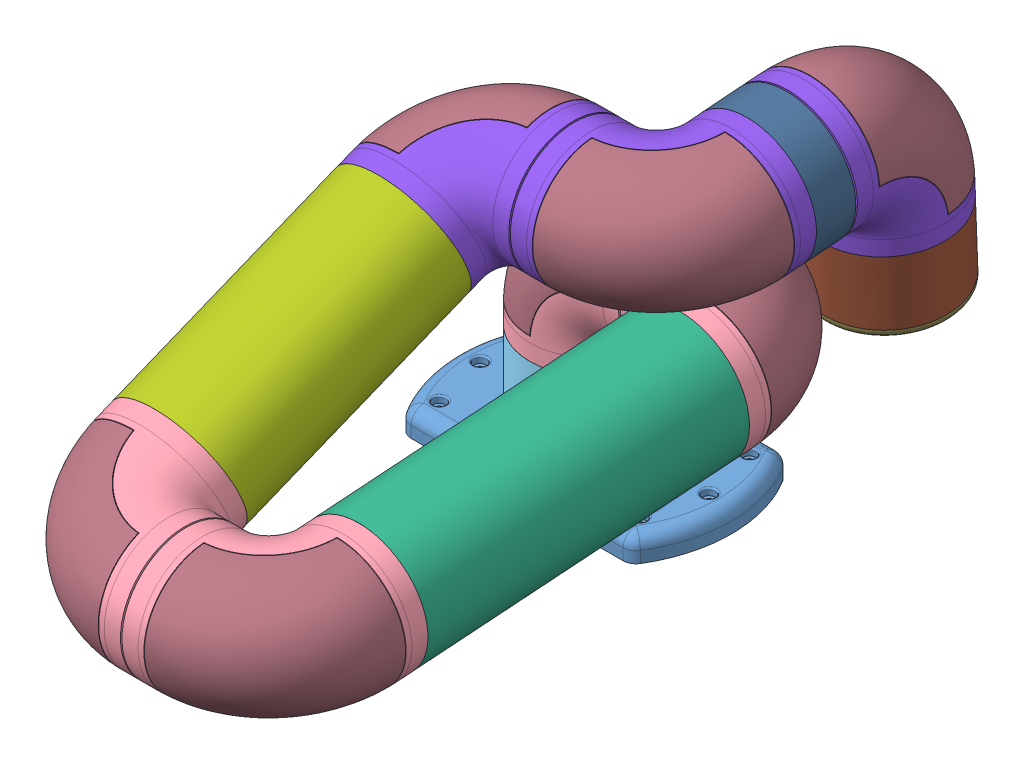
SolidWorks assembly LEG_ACTIVE, configuration 默认. Lengths in mm.
Overall size (249.75 258.63 494.76).
28 component instances, 13 part files, 66 mates.
Components (placement in the parent):
- A1-1: A1 [默认] at (-3.0825 -30.4263 170) size (170 15 96)
- 4340_sim-1: 4340_sim [默认] at (-3.0825 -31.4263 170) size (57 53.25 57)
- A2-1: A2 [默认] at (-3.0825 -0.4263 170) x (0.707107 0 -0.707107) z (-0.707107 0 -0.707107) size (80 15 80)
- B1-1: B1 [默认] at (-3.0825 39.8237 170) size (96.96 109.09 84.56)
- L1-1: L1 [默认] at (-3.0825 0.5237 170) size (80 39.3 80)
- 4340_sim-2: 4340_sim [默认] at (9.7675 94.8237 170) x (0 -1 0) z (0 0 1) size (57 53.25 57)
- B1-2: B1 [默认] at (107.8675 90.9989 224.8669) x (-1 0 0) z (0 -0.997579 -0.06954) size (96.96 109.09 84.56)
- L2-1: L2 [默认] at (107.8675 77.0909 424.3827) x (1 0 0) z (0 0.997579 0.06954) size (80 200 80)
- B1-3: B1 [默认] at (107.8675 77.0909 424.3827) x (-1 0 0) z (0 0.997579 0.06954) size (96.96 109.09 84.56)
- 4340_sim-3: 4340_sim [默认] at (95.0175 73.2662 479.2495) x (0 1 0) z (0 0 1) size (57 53.25 57)
- B1-4: B1 [默认] at (-3.0825 93.8666 428.2533) x (1 0 0) z (0 -0.927205 -0.374554) size (96.96 109.09 84.56)
- L3-1: L3 [默认] at (-3.0825 150.0497 289.1725) x (1 0 0) z (0 -0.927205 -0.374554) size (80 150 80)
- B2-1: B2 [默认] at (-3.0825 150.0497 289.1725) x (1 0 0) z (0 0.927205 0.374554) size (96.96 109.09 84.56)
- B2-2: B2 [默认] at (107.9175 174.8831 183.3393) x (-1 0 0) z (0 0.997034 0.076963) size (96.96 109.09 84.56)
- DM4310_sim-1: DM4310_sim [默认] at (5.6139 -14.4916 258.1062) x (0 -0.117702 -0.993049) z (0.993049 -0.116884 0.013854) size (57 61.9 51.54)
- DM4310_sim-2: DM4310_sim [默认] at (106.1306 358.8556 219.409) x (0.999793 0.020275 0.001565) z (-0.002394 0.193757 -0.981047) size (57 61.9 51.54)
- L4-1: L4 [默认] at (107.9175 174.8831 183.3393) x (1 0 0) z (0 0.997034 0.076963) size (80 24.5 80)
- B2-3: B2 [默认] at (105.6912 126.2867 98.8486) x (0 -0.076963 0.997034) z (-0.99918 0.040357 0.003115) size (96.96 109.09 84.56)
- DM4310_sim-3: DM4310_sim [默认] at (166.0013 159.1883 -75.5941) x (0.950216 -0.062177 0.305326) z (-0.003831 -0.982146 -0.188081) size (57 61.9 51.54)
- L6-1: L6 [默认] at (103.9912 84.4456 95.6188) x (-0.798046 0.078544 -0.597456) z (0.601235 0.037187 -0.798206) size (80 42 80)
- L7-1: L7 [默认] at (103.9912 84.4456 95.6188) x (0.982582 -0.053657 0.177917) z (0.18137 0.068359 -0.981036) size (80 14.5 80)
- C1-1: C1 [默认] at (107.8675 90.9989 224.8669) x (-1 0 0) z (0 -0.997579 -0.06954) size (83.14 83.47 85.73)
- C1-2: C1 [默认] at (-3.0825 39.8237 170) size (83.14 83.47 85.73)
- C1-3: C1 [默认] at (107.8675 77.0909 424.3827) x (-1 0 0) z (0 0.997579 0.06954) size (83.14 83.47 85.73)
- C1-4: C1 [默认] at (-3.0825 93.8666 428.2533) x (1 0 0) z (0 -0.927205 -0.374554) size (83.14 83.47 85.73)
- C1-5: C1 [默认] at (-3.0825 150.0497 289.1725) x (1 0 0) z (0 0.927205 0.374554) size (83.14 83.47 85.73)
- C1-6: C1 [默认] at (107.9175 174.8831 183.3393) x (-1 0 0) z (0 0.997034 0.076963) size (83.14 83.47 85.73)
- C1-7: C1 [默认] at (105.6912 126.2867 98.8486) x (0 -0.076963 0.997034) z (-0.99918 0.040357 0.003115) size (83.14 83.47 85.73)
Mates (geometry in assembly coordinates):
- 重合1: coincident anti-aligned: plane of A1-1 through (-3.0825 -15.4263 170) normal (0 1 0); plane of 4340_sim-1 through (-3.0825 -15.4263 170) normal (0 -1 0)
- 同心1: concentric aligned: cylinder of A1-1 through (-16.5176 -15.4263 183.435) axis (0 -1 0) radius 1.6; cylinder of 4340_sim-1 through (-16.5176 -11.4263 183.435) axis (0 -1 0) radius 1.5
- 同心2: concentric aligned: cylinder of A1-1 through (10.3525 -15.4263 156.565) axis (0 -1 0) radius 1.6; cylinder of 4340_sim-1 through (10.3525 -11.4263 156.565) axis (0 -1 0) radius 1.5
- 重合2: coincident anti-aligned: plane of A1-1 through (-3.0825 -15.4263 170) normal (0 1 0); plane of A2-1 through (-3.0825 -15.4263 170) normal (0 -1 0)
- 同心3: concentric anti-aligned: cylinder of A1-1 through (21.3127 -15.4263 194.3952) axis (0 -1 0) radius 1.6; cylinder of A2-1 through (21.3127 -15.4263 194.3952) axis (0 1 0) radius 1.6
- 同心4: concentric anti-aligned: cylinder of A1-1 through (21.3127 -15.4263 145.6048) axis (0 -1 0) radius 1.6; cylinder of A2-1 through (21.3127 -15.4263 145.6048) axis (0 1 0) radius 1.6
- 重合3: coincident anti-aligned: plane of 4340_sim-1 through (-3.0825 37.8237 170) normal (0 1 0); plane of B1-1 through (-3.0825 37.8237 170) normal (0 -1 0)
- 同心5: concentric anti-aligned: cylinder of 4340_sim-1 through (-3.0825 36.8237 170) axis (0 -1 0) radius 28.5; cylinder of B1-1 through (-3.0825 27.8237 170) axis (0 1 0) radius 33.5
- 同心6: concentric anti-aligned: cylinder of B1-1 through (-3.0825 37.8237 170) axis (0 1 0) radius 37.8; cylinder of L1-1 through (-3.0825 39.8237 170) axis (0 -1 0) radius 38
- 重合4: coincident anti-aligned: plane of B1-1 through (-3.0825 39.8237 170) normal (0 -1 0); plane of L1-1 through (-3.0825 39.8237 170) normal (0 1 0)
- 重合5: coincident anti-aligned: plane of B1-1 through (25.7675 94.8237 170) normal (1 0 0); plane of 4340_sim-2 through (25.7675 94.8237 170) normal (-1 0 0)
- 同心7: concentric anti-aligned: cylinder of B1-1 through (-45.0452 108.2587 183.435) axis (1 0 0) radius 1.6; cylinder of 4340_sim-2 through (29.7675 108.2587 183.435) axis (-1 0 0) radius 1.5
- 同心8: concentric anti-aligned: cylinder of B1-1 through (-45.0452 81.3886 156.565) axis (1 0 0) radius 1.6; cylinder of 4340_sim-2 through (29.7675 81.3886 156.565) axis (-1 0 0) radius 1.5
- 重合6: coincident anti-aligned: plane of 4340_sim-2 through (79.0175 94.8237 170) normal (1 0 0); plane of B1-2 through (79.0175 94.8237 170) normal (-1 0 0)
- 同心9: concentric aligned: cylinder of 4340_sim-2 through (78.0175 94.8237 170) axis (-1 0 0) radius 28.5; cylinder of B1-2 through (62.8675 94.8237 170) axis (-1 0 0) radius 37
- 同心10: concentric anti-aligned: cylinder of B1-2 through (107.8675 90.8599 226.862) axis (0 0.06954 -0.997579) radius 37.8; cylinder of L2-1 through (107.8675 90.9989 224.8669) axis (0 -0.06954 0.997579) radius 38
- 同心11: concentric aligned: cylinder of L2-1 through (107.8675 90.9989 224.8669) axis (0 -0.06954 0.997579) radius 38; cylinder of B1-3 through (107.8675 77.23 422.3875) axis (0 -0.06954 0.997579) radius 37.8
- 重合8: coincident anti-aligned: plane of L2-1 through (107.8675 77.0909 424.3827) normal (0 -0.06954 0.997579); plane of B1-3 through (107.8675 77.0909 424.3827) normal (0 0.06954 -0.997579)
- 重合9: coincident aligned: plane of B1-2 through (52.8675 94.8237 170) normal (-1 0 0); plane of B1-3 through (52.8675 73.2662 479.2495) normal (-1 0 0)
- 重合10: coincident anti-aligned: plane of B1-3 through (79.0175 73.2662 479.2495) normal (-1 0 0); plane of 4340_sim-3 through (79.0175 73.2662 479.2495) normal (1 0 0)
- 同心12: concentric anti-aligned: cylinder of B1-3 through (62.8675 73.2662 479.2495) axis (-1 0 0) radius 37; cylinder of 4340_sim-3 through (26.7675 73.2662 479.2495) axis (1 0 0) radius 28.5
- 重合11: coincident anti-aligned: plane of 4340_sim-3 through (25.7675 73.2662 479.2495) normal (-1 0 0); plane of B1-4 through (25.7675 73.2662 479.2495) normal (1 0 0)
- 同心13: concentric aligned: cylinder of 4340_sim-3 through (26.7675 73.2662 479.2495) axis (1 0 0) radius 28.5; cylinder of B1-4 through (41.9175 73.2662 479.2495) axis (1 0 0) radius 37
- 重合12: coincident anti-aligned: plane of B1-4 through (-3.0825 93.8666 428.2533) normal (0 0.374554 -0.927205); plane of L3-1 through (-3.0825 93.8666 428.2533) normal (0 -0.374554 0.927205)
- 同心14: concentric anti-aligned: cylinder of B1-4 through (-3.0825 94.6158 426.3988) axis (0 -0.374554 0.927205) radius 37.8; cylinder of L3-1 through (-3.0825 93.8666 428.2533) axis (0 0.374554 -0.927205) radius 38
- 同心15: concentric aligned: cylinder of L3-1 through (-3.0825 93.8666 428.2533) axis (0 0.374554 -0.927205) radius 38; cylinder of B2-1 through (-3.0825 149.3006 291.0269) axis (0 0.374554 -0.927205) radius 37.8
- 重合13: coincident anti-aligned: plane of L3-1 through (-3.0825 150.0497 289.1725) normal (0 0.374554 -0.927205); plane of B2-1 through (-3.0825 150.0497 289.1725) normal (0 -0.374554 0.927205)
- 重合14: coincident aligned: plane of B1-4 through (51.9175 73.2662 479.2495) normal (1 0 0); plane of B2-1 through (51.9175 170.6502 238.1762) normal (1 0 0)
- 重合15: coincident anti-aligned: plane of B2-1 through (29.4175 170.6502 238.1762) normal (1 0 0); plane of DM4310_sim-1 through (29.4175 170.6502 238.1762) normal (-1 0 0)
- 同心16: concentric anti-aligned: cylinder of B2-1 through (41.9175 170.6502 238.1762) axis (1 0 0) radius 37; cylinder of DM4310_sim-1 through (74.4175 170.6502 238.1762) axis (-1 0 0) radius 28.5
- 重合16: coincident anti-aligned: plane of B2-2 through (75.4175 170.6502 238.1762) normal (-1 0 0); plane of DM4310_sim-1 through (75.4175 170.6502 238.1762) normal (1 0 0)
- 同心17: concentric aligned: cylinder of B2-2 through (62.9175 170.6502 238.1762) axis (-1 0 0) radius 37; cylinder of DM4310_sim-1 through (74.4175 170.6502 238.1762) axis (-1 0 0) radius 28.5
- 重合17: coincident anti-aligned: plane of B2-2 through (107.9175 175.0371 181.3453) normal (0 0.076963 -0.997034); plane of DM4310_sim-2 through (107.9175 175.0371 181.3453) normal (0 -0.076963 0.997034)
- 同心18: concentric aligned: cylinder of B2-2 through (107.9175 175.8067 171.3749) axis (0 -0.076963 0.997034) radius 33.5; cylinder of DM4310_sim-2 through (107.9175 178.5004 136.4787) axis (0 -0.076963 0.997034) radius 28.5
- 重合18: coincident anti-aligned: plane of B2-2 through (107.9175 174.8831 183.3393) normal (0 0.076963 -0.997034); plane of L4-1 through (107.9175 174.8831 183.3393) normal (0 -0.076963 0.997034)
- 同心19: concentric aligned: cylinder of B2-2 through (107.9175 175.0371 181.3453) axis (0 -0.076963 0.997034) radius 37.8; cylinder of L4-1 through (107.9175 176.7687 158.912) axis (0 -0.076963 0.997034) radius 38
- 重合19: coincident anti-aligned: plane of DM4310_sim-2 through (107.9175 178.5774 135.4817) normal (0 0.076963 -0.997034); plane of B2-3 through (107.9175 178.5774 135.4817) normal (0 -0.076963 0.997034)
- 同心20: concentric aligned: cylinder of DM4310_sim-2 through (107.9175 178.5004 136.4787) axis (0 -0.076963 0.997034) radius 28.5; cylinder of B2-3 through (107.9175 177.6153 147.9446) axis (0 -0.076963 0.997034) radius 37
- 重合20: coincident anti-aligned: plane of B2-3 through (105.6103 124.2943 98.6948) normal (-0.040477 -0.996217 -0.0769); plane of DM4310_sim-3 through (105.6103 124.2943 98.6948) normal (0.040477 0.996217 0.0769)
- 同心21: concentric aligned: cylinder of B2-3 through (105.2055 114.3321 97.9258) axis (0.040477 0.996217 0.0769) radius 33.5; cylinder of DM4310_sim-3 through (103.7888 79.4646 95.2343) axis (0.040477 0.996217 0.0769) radius 28.5
- 重合21: coincident anti-aligned: plane of B2-3 through (105.6912 126.2867 98.8486) normal (-0.040477 -0.996217 -0.0769); plane of L6-1 through (105.6912 126.2867 98.8486) normal (0.040477 0.996217 0.0769)
- 同心22: concentric anti-aligned: cylinder of B2-3 through (105.6103 124.2943 98.6948) axis (0.040477 0.996217 0.0769) radius 37.8; cylinder of L6-1 through (105.6912 126.2867 98.8486) axis (-0.040477 -0.996217 -0.0769) radius 38
- 同心23: concentric aligned: cylinder of L6-1 through (105.6912 126.2867 98.8486) axis (-0.040477 -0.996217 -0.0769) radius 38; cylinder of L7-1 through (104.396 94.4078 96.3878) axis (-0.040477 -0.996217 -0.0769) radius 37.8
- 重合22: coincident anti-aligned: plane of L6-1 through (103.9912 84.4456 95.6188) normal (-0.040477 -0.996217 -0.0769); plane of L7-1 through (103.9912 84.4456 95.6188) normal (0.040477 0.996217 0.0769)
- 重合24: coincident anti-aligned: plane of B1-2 through (107.8675 90.9989 224.8669) normal (0 -0.06954 0.997579); plane of L2-1 through (107.8675 90.9989 224.8669) normal (0 0.06954 -0.997579)
- 平行1: parallel anti-aligned: plane of B1-2 through (147.7939 131.8434 214.1457) normal (0 0.06954 -0.997579); plane of C1-1 through (147.78 131.8657 213.8262) normal (0 -0.06954 0.997579)
- 同心24: concentric aligned: cylinder of B1-2 through (62.8675 131.5975 217.6727) axis (0 -0.997579 -0.06954) radius 45; cylinder of C1-1 through (62.8675 131.5975 217.6727) axis (0 -0.997579 -0.06954) radius 45.3244
- 相切1: tangent aligned: cylinder of B1-2 through (107.8675 90.9989 224.8669) axis (0 0.06954 -0.997579) radius 40; torus of C1-1
- 平行3: parallel anti-aligned: plane of B1-1 through (-43.009 53.3592 130) normal (0 1 0); plane of C1-2 through (-42.995 53.6795 130) normal (0 -1 0)
- 同心27: concentric aligned: cylinder of B1-1 through (41.9175 49.8237 130) axis (0 0 1) radius 45; cylinder of C1-2 through (41.9175 49.8237 130) axis (0 0 1) radius 45.3244
- 相切2: tangent aligned: cylinder of B1-1 through (-3.0825 39.8237 170) axis (0 1 0) radius 40; torus of C1-2
- 平行4: parallel anti-aligned: plane of B1-3 through (147.7939 36.2465 435.1038) normal (0 -0.06954 0.997579); plane of C1-3 through (147.78 36.2242 435.4234) normal (0 0.06954 -0.997579)
- 同心28: concentric aligned: cylinder of B1-3 through (62.8675 36.4923 431.5769) axis (0 0.997579 0.06954) radius 45; cylinder of C1-3 through (62.8675 36.4923 431.5769) axis (0 0.997579 0.06954) radius 45.3244
- 相切3: tangent aligned: cylinder of B1-3 through (62.8675 73.2662 479.2495) axis (-1 0 0) radius 40; torus of C1-3
- 平行5: parallel anti-aligned: plane of B1-4 through (-43.009 125.8851 455.7856) normal (0 -0.374554 0.927205); plane of C1-4 through (-42.995 125.7651 456.0826) normal (0 0.374554 -0.927205)
- 同心29: concentric aligned: cylinder of B1-4 through (41.9175 127.2093 452.5075) axis (0 -0.927205 -0.374554) radius 45; cylinder of C1-4 through (41.9175 127.2093 452.5075) axis (0 -0.927205 -0.374554) radius 45.3244
- 相切4: tangent aligned: cylinder of B1-4 through (-3.0825 93.8666 428.2533) axis (0 -0.374554 0.927205) radius 40; torus of C1-4
- 平行6: parallel anti-aligned: plane of B2-1 through (-43.009 118.0313 261.6401) normal (0 0.374554 -0.927205); plane of C1-5 through (-42.995 118.1513 261.3431) normal (0 -0.374554 0.927205)
- 同心30: concentric aligned: cylinder of B2-1 through (41.9175 116.707 264.9183) axis (0 0.927205 0.374554) radius 45; cylinder of C1-5 through (41.9175 116.707 264.9183) axis (0 0.927205 0.374554) radius 45.3244
- 相切5: tangent aligned: cylinder of B2-1 through (-3.0825 150.0497 289.1725) axis (0 0.374554 -0.927205) radius 40; torus of C1-5
- 平行7: parallel anti-aligned: plane of B2-2 through (147.8439 133.96 193.7562) normal (0 -0.076963 0.997034); plane of C1-6 through (147.83 133.9354 194.0756) normal (0 0.076963 -0.997034)
- 同心31: concentric aligned: cylinder of B2-2 through (62.9175 134.2322 190.2311) axis (0 0.997034 0.076963) radius 45; cylinder of C1-6 through (62.9175 134.2322 190.2311) axis (0 0.997034 0.076963) radius 45.3244
- 相切6: tangent aligned: cylinder of B2-2 through (62.9175 170.6502 238.1762) axis (-1 0 0) radius 40; torus of C1-6
- 平行10: parallel anti-aligned: plane of B2-3 through (146.2063 141.2297 59.9568) normal (0.040477 0.996217 0.0769); plane of C1-7 through (146.2193 141.5477 59.9954) normal (-0.040477 -0.996217 -0.0769)
- 同心34: concentric aligned: cylinder of B2-3 through (146.0632 131.1713 144.3595) axis (-0.99918 0.040357 0.003115) radius 45; cylinder of C1-7 through (146.0632 131.1713 144.3595) axis (-0.99918 0.040357 0.003115) radius 45.3244
- 相切8: tangent aligned: cylinder of B2-3 through (107.9175 177.6153 147.9446) axis (0 -0.076963 0.997034) radius 40; torus of C1-7
